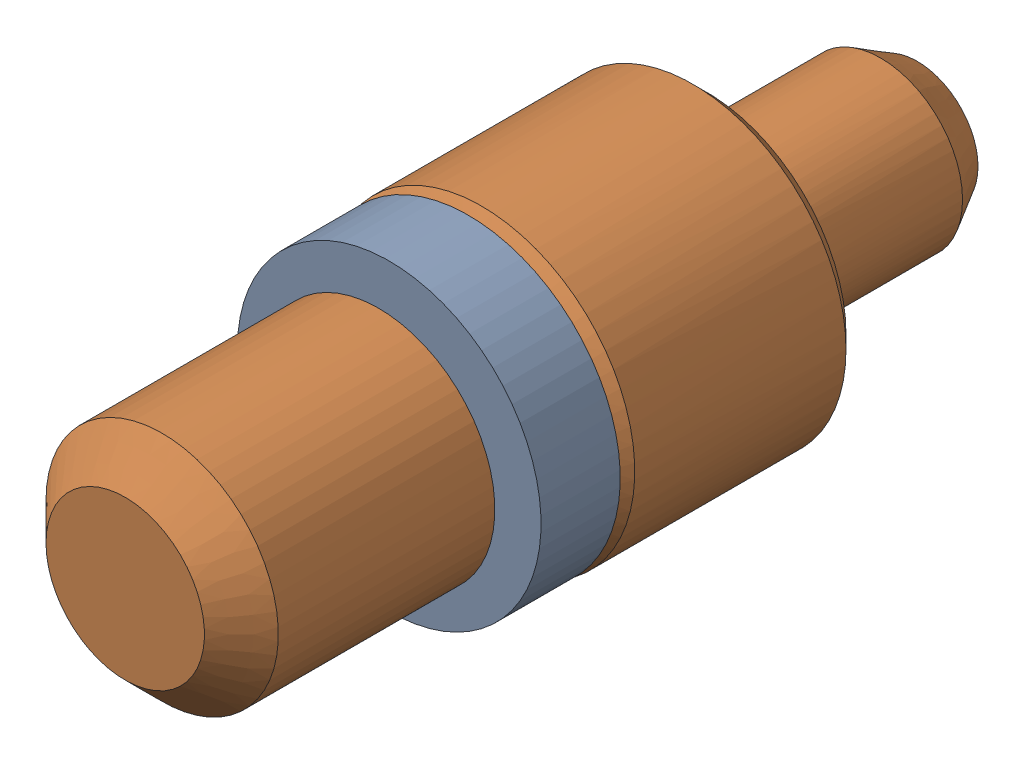
SolidWorks assembly Pogo Pin Asmbly_6, configuration Default. Lengths in mm.
Overall size (2.95 2.95 7.62).
2 component instances, 2 part files, 0 mates.
Components (placement in the parent):
- Pogo O-Ring-1: Pogo O-Ring [Default] at (76.407 43.1359 -6.223) size (2.92 2.92 0.76)
- Pogo Contact Pin-1: Pogo Contact Pin [Default] at (76.407 43.1359 -6.223) size (2.95 2.95 7.62)
